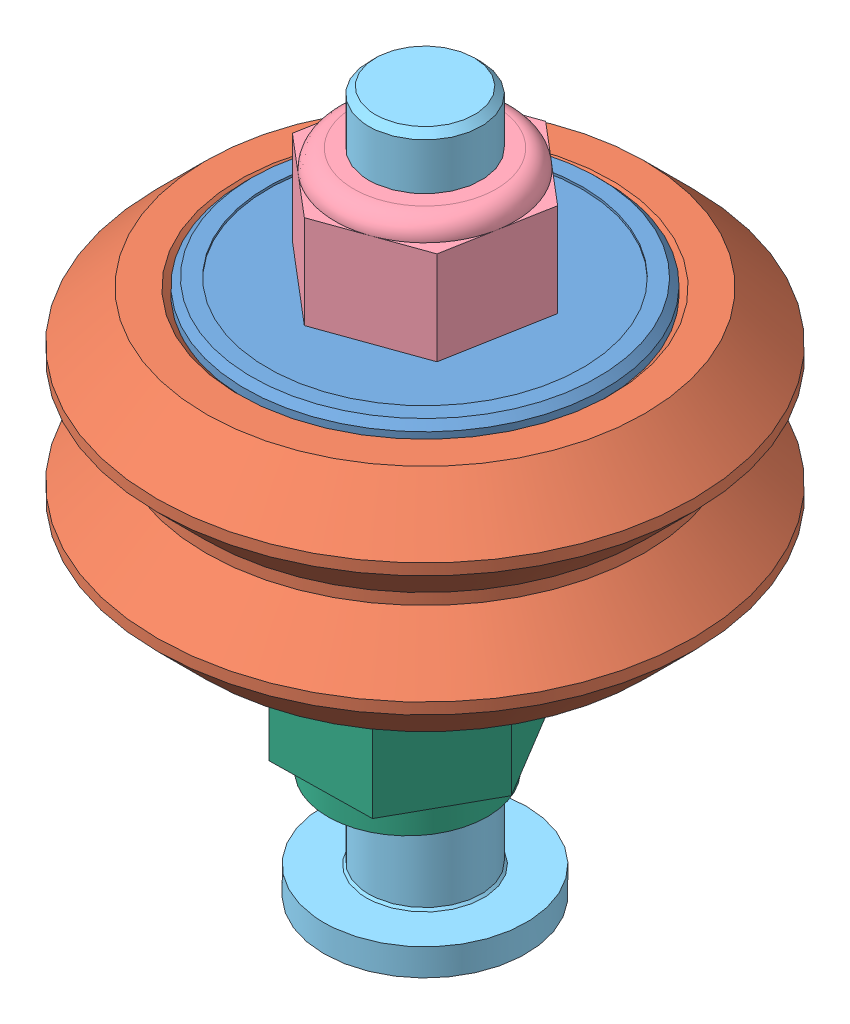
SolidWorks assembly Dual_V_Wheel_Bolt_Assembly_Eccentric, configuration Default. Lengths in mm.
Overall size (33.21 31.5 33.21).
7 component instances, 6 part files, 11 mates.
Components (placement in the parent):
- Ball_Bearing_625_2RS-1: Ball_Bearing_625_2RS [Défaut] at (0 15.634 0) x (-1 0 0) z (0 0 1) size (16 5 16)
- Ball_Bearing_625_2RS-2: Ball_Bearing_625_2RS [Défaut] at (0 21.634 0) x (-0.965595 0 -0.260051) z (-0.260051 0 0.965595) size (16 5 16)
- Dual_V_Wheel_Delrin_(5mm_Bore)-1: Dual_V_Wheel_Delrin_(5mm_Bore) [Défaut] at (0 13.519 0) x (0.565015 0 -0.825081) z (0.825081 0 0.565015) size (23.89 10.23 23.89)
- Precision_Shim_10x5x1mm-1: Precision_Shim_10x5x1mm [Default] at (0 18.634 0) x (-0.674323 0 -0.738436) z (-0.738436 0 0.674323) size (10 1 10)
- Nylon_Insert_Hex_Locknut_5mm-1: Nylon_Insert_Hex_Locknut_5mm [Default] at (0 24.134 0) x (0.336542 0 0.941668) z (-0.941668 0 0.336542) size (8 4.99 9.24)
- M5_Low_Profile_Screw_30mm-1: M5_Low_Profile_Screw_30mm [Default] at origin size (9 31.5 9)
- Eccentric_Spacer-1: Eccentric_Spacer [Défaut] at (0.0131 6.784 0.7899) x (0.999862 0 -0.016613) z (0 1 0) size (9.99 7.87 7.62)
Mates (geometry in assembly coordinates):
- Concentric3: concentric anti-aligned: cylinder of Ball_Bearing_625_2RS-1 through (0 15.634 0) axis (0 1 0) radius 8; cylinder of Dual_V_Wheel_Delrin_(5mm_Bore)-1 through (0 13.519 0) axis (0 -1 0) radius 7.987
- Coincident2: coincident anti-aligned: plane of Ball_Bearing_625_2RS-1 through (-7 18.134 0) normal (0 1 0); plane of Dual_V_Wheel_Delrin_(5mm_Bore)-1 through (4.5128 18.134 -6.5899) normal (0 -1 0)
- Coincident3: coincident anti-aligned: plane of Ball_Bearing_625_2RS-1 through (-2.8 18.134 0) normal (0 1 0); plane of Precision_Shim_10x5x1mm-1 through (0 18.134 0) normal (0 -1 0)
- Coincident4: coincident anti-aligned: plane of Ball_Bearing_625_2RS-2 through (-6.7592 19.134 -1.8204) normal (0 -1 0); plane of Dual_V_Wheel_Delrin_(5mm_Bore)-1 through (4.5128 19.134 -6.5899) normal (0 1 0)
- Coincident6: coincident anti-aligned: plane of Ball_Bearing_625_2RS-2 through (-2.7037 24.134 -0.7281) normal (0 1 0); plane of Nylon_Insert_Hex_Locknut_5mm-1 through (0 24.134 0) normal (0 -1 0)
- Concentric5: concentric anti-aligned: cylinder of Precision_Shim_10x5x1mm-1 through (0 18.134 0) axis (0 1 0) radius 2.5; cylinder of M5_Low_Profile_Screw_30mm-1 through (0 31.5 0) axis (0 -1 0) radius 2.5
- Concentric6: concentric anti-aligned: cylinder of Ball_Bearing_625_2RS-2 through (0 21.634 0) axis (0 1 0) radius 2.5; cylinder of M5_Low_Profile_Screw_30mm-1 through (0 31.5 0) axis (0 -1 0) radius 2.5
- Concentric7: concentric aligned: cylinder of Nylon_Insert_Hex_Locknut_5mm-1 through (0 24.134 0) axis (0 -1 0) radius 2.1; cylinder of M5_Low_Profile_Screw_30mm-1 through (0 31.5 0) axis (0 -1 0) radius 2.5
- Concentric8: concentric aligned: cylinder of Dual_V_Wheel_Delrin_(5mm_Bore)-1 through (0 13.519 0) axis (0 -1 0) radius 7.987; cylinder of M5_Low_Profile_Screw_30mm-1 through (0 31.5 0) axis (0 -1 0) radius 2.5
- Concentric9: concentric anti-aligned: cylinder of M5_Low_Profile_Screw_30mm-1 through (0 31.5 0) axis (0 -1 0) radius 2.5; cylinder of Eccentric_Spacer-1 through (0 5.514 0) axis (0 1 0) radius 2.5
- Coincident7: coincident anti-aligned: plane of Ball_Bearing_625_2RS-1 through (-2.8 13.134 0) normal (0 -1 0); plane of Eccentric_Spacer-1 through (4.5562 13.134 0.7144) normal (0 1 0)
